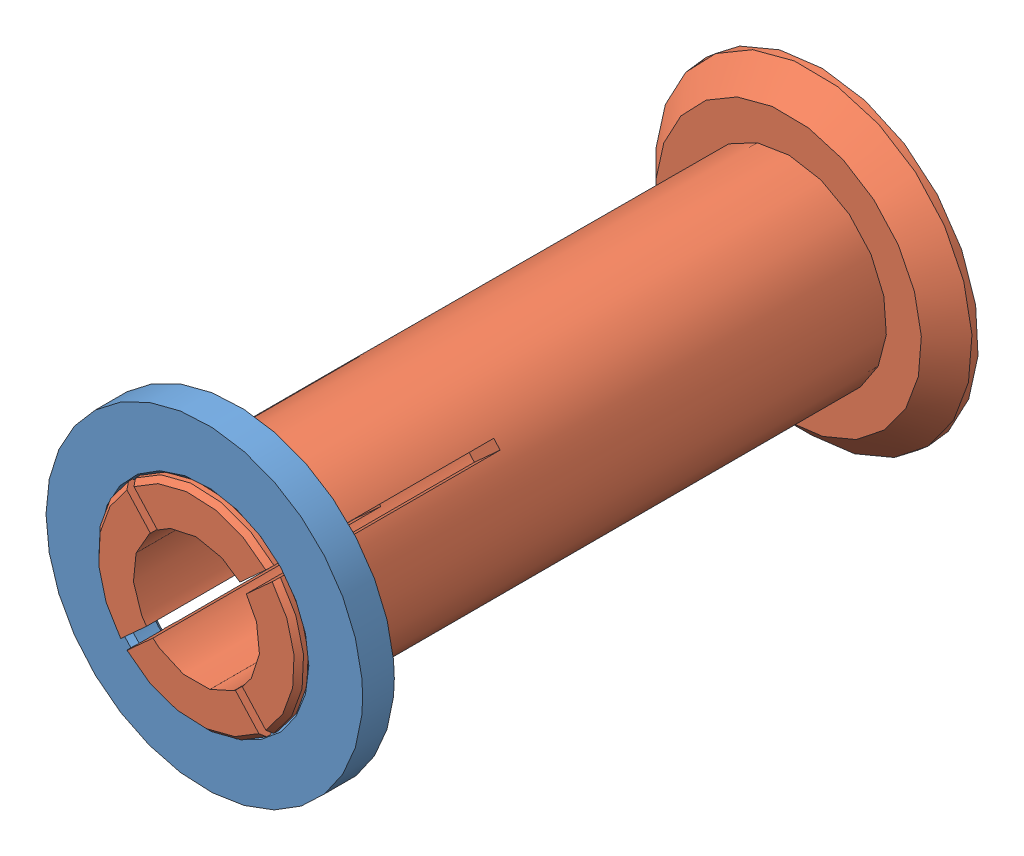
SolidWorks assembly 32-92-20-spool-adapter, configuration Default. Lengths in mm.
Overall size (70.63 70.63 98.5).
2 component instances, 2 part files, 1 mates.
Components (placement in the parent):
- 32-92-20-spool-adapter-female-1: 32-92-20-spool-adapter-female [Default] at (-0.1477 21.8673 48.6765) size (50 50 5)
- 32-92-20-spool-adapter-male-1: 32-92-20-spool-adapter-male [Default] at (-0.1477 21.8673 -38.5735) x (0.739739 0.672894 0) z (0 0 1) size (50 50 98.5)
Mates (geometry in assembly coordinates):
- Coincident1: coincident aligned: cone of 32-92-20-spool-adapter-female-1 through (-0.1477 21.8673 53.6765) axis (0 0 -1); cone of 32-92-20-spool-adapter-male-1 through (-0.1477 21.8673 53.4265) axis (0 0 -1)
